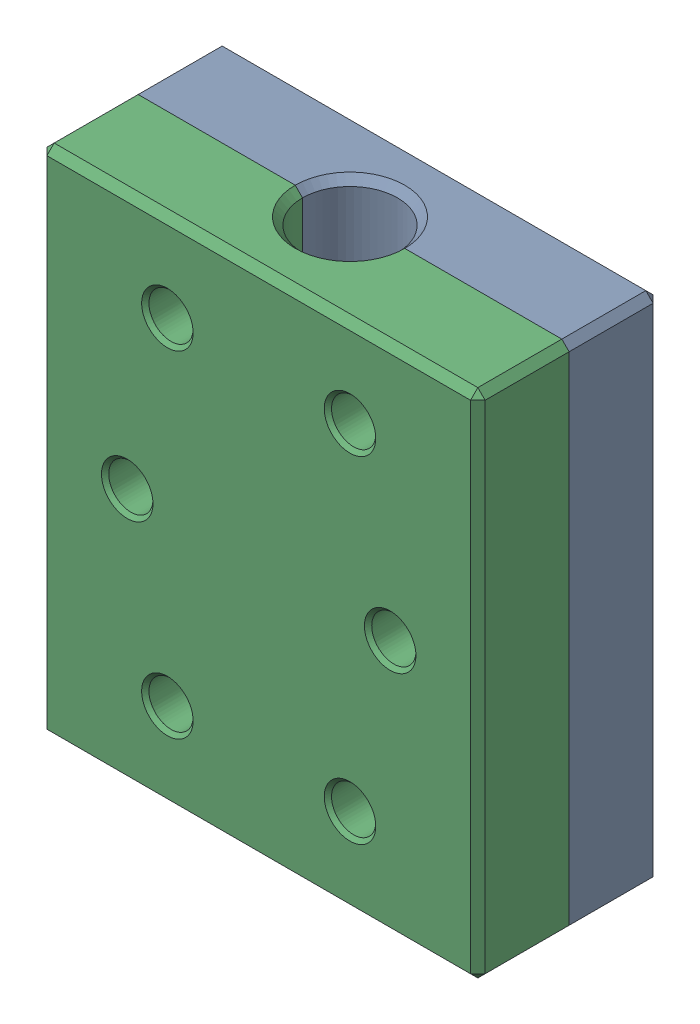
SolidWorks assembly Lead Screw Nut Assembly, configuration Default. Lengths in mm.
Overall size (60 70 25).
3 component instances, 2 part files, 0 mates.
Components (placement in the parent):
- Lead Screw Nut Clamshell-1: Lead Screw Nut Clamshell [Default] at origin size (60 70 12.5)
- MISUMI Brass Lead Screw Flange Nut - MTSGR12-1: MISUMI Brass Lead Screw Flange Nut - MTSGR12 [Default] at (0 -15 30) x (0 1 0) z (0 0 1) size (30 44 24)
- Lead Screw Nut Clamshell-2: Lead Screw Nut Clamshell [Default] at (0 0 60) x (-1 0 0) z (0 0 -1) size (60 70 12.5)
